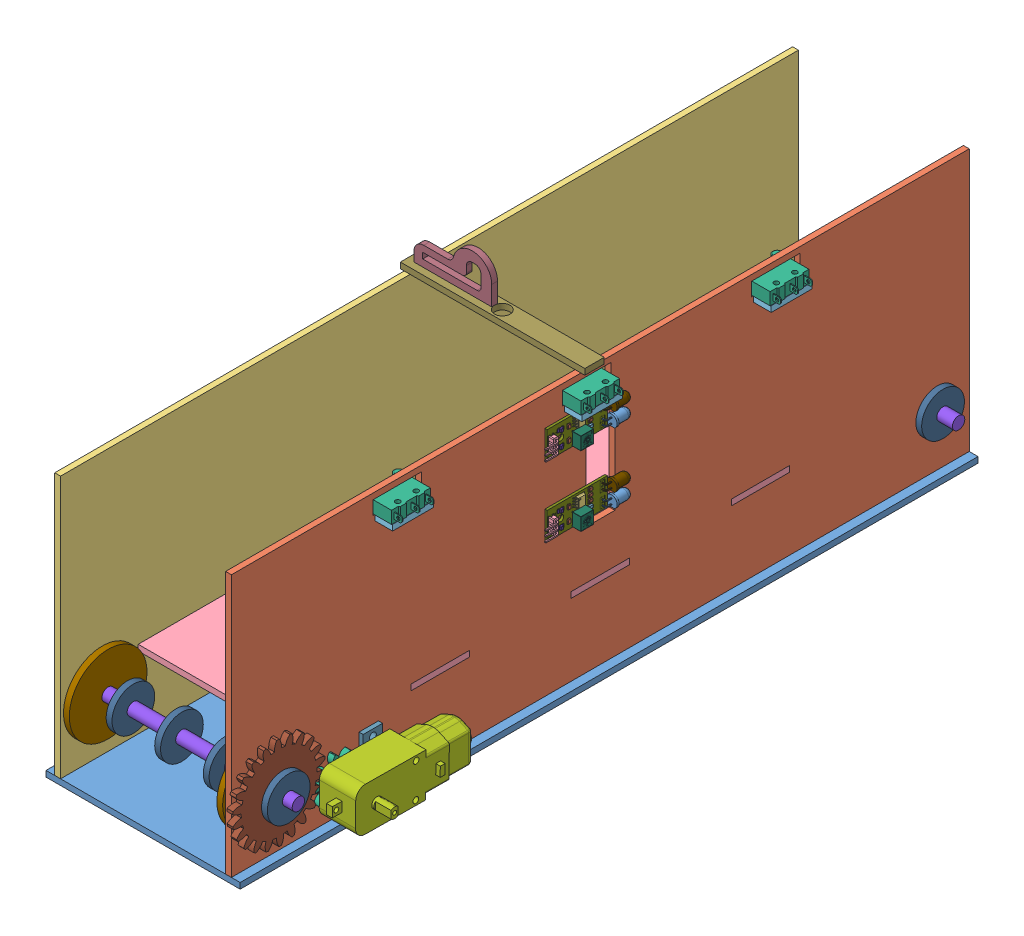
SolidWorks assembly EnsambleBandaConSensores, configuration Predeterminado. Lengths in mm.
Overall size (128.87 161.82 399.89).
68 component instances, 24 part files, 79 mates.
Components (placement in the parent):
- BAseGeneral-1: BAseGeneral [Predeterminado] at (-4.2266 -31.7563 350) size (100 3 380)
- ParedDerecha-2: ParedDerecha [Predeterminado] at (38.2734 38.7437 350) x (0 0 -1) z (1 0 0) size (380 138 3)
- ParedIzquierda-1: ParedIzquierda [Predeterminado] at (-46.7266 38.7437 350) x (0 0 1) z (-1 0 0) size (380 138 3)
- base-1: base [Predeterminado] at (-4.2266 8.2437 350) size (91 3 300)
- soporteFinCarrera-1: soporteFinCarrera [Predeterminado] at (38.2734 93.2437 265.5) x (0 0 -1) z (1 0 0) size (21 3 12)
- soporteFinCarrera-2: soporteFinCarrera [Predeterminado] at (38.2734 93.2437 460.5) x (0 0 -1) z (1 0 0) size (21 3 12)
- soporteFinCarrera-3: soporteFinCarrera [Predeterminado] at (38.2734 93.2437 363) x (0 0 -1) z (1 0 0) size (21 3 12)
- MiEngranePequeñoV2-1: MiEngranePequeñoV2 [Predeterminado] at (42.7734 384.4008 222.5284) x (0 -0.999961 0.008878) z (0 0.008878 0.999961) size (23.7 3 23.48)
- Motor-1: Motor [Predeterminado] at (65.5434 -8.5781 489.3215) x (0 -0.008878 -0.999961) z (0 0.999961 -0.008878) size (70.2 36.87 22.3)
- ejeRuedas-1: ejeRuedas [Predeterminado] at (55.7734 1.2437 520) x (0 1 0) z (0 0 1) size (6.4 110 6.4)
- RuedaGrande-1: RuedaGrande [Predeterminado] at (-42.2266 1.2437 520) x (0 1 0) z (0 0 1) size (40 3 40)
- RuedaGrande-2: RuedaGrande [Predeterminado] at (36.7734 1.2437 520) x (0 1 0) z (0 0 1) size (40 3 40)
- ruedaPequeña-1: ruedaPequeña [Predeterminado] at (-29.2266 1.2437 520) x (0 1 0) z (0 0 1) size (22 3 22)
- ruedaPequeña-2: ruedaPequeña [Predeterminado] at (-4.2266 1.2437 520) x (0 1 0) z (0 0 1) size (22 3 22)
- ruedaPequeña-3: ruedaPequeña [Predeterminado] at (20.7734 1.2437 520) x (0 1 0) z (0 0 1) size (22 3 22)
- EngraneGrande-1: EngraneGrande [Predeterminado] at (42.7734 -30.0906 1041.862) x (0 0.673646 -0.739054) z (1 0 0) size (48.01 47.68 3)
- ruedaPequeña-4: ruedaPequeña [Predeterminado] at (47.7734 1.2437 520) x (0 -1 0) z (0 0 1) size (22 3 22)
- ruedaPequeña-5: ruedaPequeña [Predeterminado] at (-53.2266 1.2437 520) x (0 -1 0) z (0 0 1) size (22 3 22)
- ejeRuedas-2: ejeRuedas [Predeterminado] at (55.7734 1.2437 180) x (0 1 0) z (0 0 1) size (6.4 110 6.4)
- ruedaPequeña-6: ruedaPequeña [Predeterminado] at (-50.2266 1.2437 180) x (0 1 0) z (0 0 1) size (22 3 22)
- ruedaPequeña-7: ruedaPequeña [Predeterminado] at (-4.2266 1.2437 180) x (0 1 0) z (0 0 1) size (22 3 22)
- ruedaPequeña-8: ruedaPequeña [Predeterminado] at (20.7734 1.2437 180) x (0 1 0) z (0 0 1) size (22 3 22)
- RuedaGrande-3: RuedaGrande [Predeterminado] at (-41.2266 1.2437 180) x (0 1 0) z (0 0 1) size (40 3 40)
- RuedaGrande-4: RuedaGrande [Predeterminado] at (32.7734 1.2437 180) x (0 -0.381849 0.924225) z (0 0.924225 0.381849) size (40 3 40)
- ruedaPequeña-9: ruedaPequeña [Predeterminado] at (47.7734 1.2437 180) x (0 1 0) z (0 0 1) size (22 3 22)
- ruedaPequeña-10: ruedaPequeña [Predeterminado] at (-29.2266 1.2437 180) x (0 1 0) z (0 0 1) size (22 3 22)
- Travesaño-1: Travesaño [Predeterminado] at (-4.2266 106.2437 355) size (95 3 10)
- GuiaMangera-1: GuiaMangera [Predeterminado] at (-28.1798 119.2437 353.5) size (40 23 3)
- SoporteMotor-1: SoporteMotor [Predeterminado] at (40.445 -8.7563 469.3) x (0 0 -1) z (1 0 0) size (10 24 3)
- Sensor_IR.stp-1: Sensor_IR.stp [Predeterminado] at (41.6734 48.2437 363.5) x (0 0 -1) z (1 0 0) size (45.22 14 7.87)
  - 3362P-1-102LF.stp-1: 3362P-1-102LF.stp [Predeterminado] at (0.5 -3.2 1.53) x (1 0 0) z (0 -1 0) size (6.6 7.58 6.6)
  - IR_Sensor_FC-51_1.stp-1: IR_Sensor_FC-51_1.stp [Predeterminado] at origin size (31 14 1.25)
  - KPTR-3216CGCK.stp-1: KPTR-3216CGCK.stp [Predeterminado] at (-8.7 3.8 1.45) x (1 0 0) z (0 0 -1) size (3.2 1.6 1.05)
  - KPTR-3216CGCK.stp-2: KPTR-3216CGCK.stp [Predeterminado] at (-8.7 -3.8 1.45) x (1 0 0) z (0 0 -1) size (3.2 1.6 1.05)
  - LED 5mm.stp-1: LED 5mm.stp [Predeterminado] at (15.74 3.64 3) x (0 1 0) z (1 0 0) size (5.5 6.7 11.78)
  - LED 5mm_foto.stp-1: LED 5mm_foto.stp [Predeterminado] at (15.74 -3.64 3) x (0 1 0) z (1 0 0) size (5.5 6.7 11.78)
  - RESC-0805.stp-1: RESC-0805.stp [Predeterminado] at (-4.525 -3.15 1.2) x (0 -1 0) z (0 0 1) size (2.1 1.35 0.6)
  - RESC-0805.stp-2: RESC-0805.stp [Predeterminado] at (-4.525 3.25 1.2) x (0 1 0) z (0 0 1) size (2.1 1.35 0.6)
  - SOIC8-150-50.stp-1: SOIC8-150-50.stp [Predeterminado] at (0.55 3.85 1.2) x (1 0 0) z (0 -1 0) size (6 1.91 4.9)
  - 1 Pin 2.54 mm Right Angle Single Row Pin Header Male 90 degrees Needle Connector.stp-1: 1 Pin 2.54 mm Right Angle Single Row Pin Header Male 90 degrees Needle Connector.stp [Predeterminado] at (-13.5 2.54 -1.76) x (-1 0 0) z (0 0 1) size (8.45 2.54 7.3)
  - 1 Pin 2.54 mm Right Angle Single Row Pin Header Male 90 degrees Needle Connector.stp-2: 1 Pin 2.54 mm Right Angle Single Row Pin Header Male 90 degrees Needle Connector.stp [Predeterminado] at (-13.5 0 -1.76) x (-1 0 0) z (0 0 1) size (8.45 2.54 7.3)
  - 1 Pin 2.54 mm Right Angle Single Row Pin Header Male 90 degrees Needle Connector.stp-3: 1 Pin 2.54 mm Right Angle Single Row Pin Header Male 90 degrees Needle Connector.stp [Predeterminado] at (-13.5 -2.54 -1.76) x (-1 0 0) z (0 0 1) size (8.45 2.54 7.3)
  - RESC-0805.stp-3: RESC-0805.stp [Predeterminado] at (6.45 5.625 1.2) size (2.1 1.35 0.6)
  - RESC-0805.stp-4: RESC-0805.stp [Predeterminado] at (6.45 3.085 1.2) size (2.1 1.35 0.6)
  - RESC-0805.stp-5: RESC-0805.stp [Predeterminado] at (6.45 0.545 1.2) size (2.1 1.35 0.6)
  - CAPC-0805-T0.95-BN.stp-1: CAPC-0805-T0.95-BN.stp [Predeterminado] at (6.45 -1.995 1.2) size (2.1 1.35 0.95)
  - CAPC-0805-T0.95-BN.stp-2: CAPC-0805-T0.95-BN.stp [Predeterminado] at (6.45 -4.535 1.2) size (2.1 1.35 0.95)
- Sensor_IR.stp-2: Sensor_IR.stp [Predeterminado] at (41.6734 84.2437 363.5) x (0 0 -1) z (1 0 0) size (45.22 14 7.87)
  - 3362P-1-102LF.stp-1: 3362P-1-102LF.stp [Predeterminado] at (0.5 -3.2 1.53) x (1 0 0) z (0 -1 0) size (6.6 7.58 6.6)
  - IR_Sensor_FC-51_1.stp-1: IR_Sensor_FC-51_1.stp [Predeterminado] at origin size (31 14 1.25)
  - KPTR-3216CGCK.stp-1: KPTR-3216CGCK.stp [Predeterminado] at (-8.7 3.8 1.45) x (1 0 0) z (0 0 -1) size (3.2 1.6 1.05)
  - KPTR-3216CGCK.stp-2: KPTR-3216CGCK.stp [Predeterminado] at (-8.7 -3.8 1.45) x (1 0 0) z (0 0 -1) size (3.2 1.6 1.05)
  - LED 5mm.stp-1: LED 5mm.stp [Predeterminado] at (15.74 3.64 3) x (0 1 0) z (1 0 0) size (5.5 6.7 11.78)
  - LED 5mm_foto.stp-1: LED 5mm_foto.stp [Predeterminado] at (15.74 -3.64 3) x (0 1 0) z (1 0 0) size (5.5 6.7 11.78)
  - RESC-0805.stp-1: RESC-0805.stp [Predeterminado] at (-4.525 -3.15 1.2) x (0 -1 0) z (0 0 1) size (2.1 1.35 0.6)
  - RESC-0805.stp-2: RESC-0805.stp [Predeterminado] at (-4.525 3.25 1.2) x (0 1 0) z (0 0 1) size (2.1 1.35 0.6)
  - SOIC8-150-50.stp-1: SOIC8-150-50.stp [Predeterminado] at (0.55 3.85 1.2) x (1 0 0) z (0 -1 0) size (6 1.91 4.9)
  - 1 Pin 2.54 mm Right Angle Single Row Pin Header Male 90 degrees Needle Connector.stp-1: 1 Pin 2.54 mm Right Angle Single Row Pin Header Male 90 degrees Needle Connector.stp [Predeterminado] at (-13.5 2.54 -1.76) x (-1 0 0) z (0 0 1) size (8.45 2.54 7.3)
  - 1 Pin 2.54 mm Right Angle Single Row Pin Header Male 90 degrees Needle Connector.stp-2: 1 Pin 2.54 mm Right Angle Single Row Pin Header Male 90 degrees Needle Connector.stp [Predeterminado] at (-13.5 0 -1.76) x (-1 0 0) z (0 0 1) size (8.45 2.54 7.3)
  - 1 Pin 2.54 mm Right Angle Single Row Pin Header Male 90 degrees Needle Connector.stp-3: 1 Pin 2.54 mm Right Angle Single Row Pin Header Male 90 degrees Needle Connector.stp [Predeterminado] at (-13.5 -2.54 -1.76) x (-1 0 0) z (0 0 1) size (8.45 2.54 7.3)
  - RESC-0805.stp-3: RESC-0805.stp [Predeterminado] at (6.45 5.625 1.2) size (2.1 1.35 0.6)
  - RESC-0805.stp-4: RESC-0805.stp [Predeterminado] at (6.45 3.085 1.2) size (2.1 1.35 0.6)
  - RESC-0805.stp-5: RESC-0805.stp [Predeterminado] at (6.45 0.545 1.2) size (2.1 1.35 0.6)
  - CAPC-0805-T0.95-BN.stp-1: CAPC-0805-T0.95-BN.stp [Predeterminado] at (6.45 -1.995 1.2) size (2.1 1.35 0.95)
  - CAPC-0805-T0.95-BN.stp-2: CAPC-0805-T0.95-BN.stp [Predeterminado] at (6.45 -4.535 1.2) size (2.1 1.35 0.95)
- Fin_Carrera.step-1: Fin_Carrera.step [Predeterminado] at (44.9634 96.2437 456.35) x (0 0 1) z (0 -1 0) size (22.47 22.8 6.34)
- Fin_Carrera.step-2: Fin_Carrera.step [Predeterminado] at (44.9634 96.2437 358.85) x (0 0 1) z (0 -1 0) size (22.47 22.8 6.34)
- Fin_Carrera.step-3: Fin_Carrera.step [Predeterminado] at (44.9634 96.2437 261.35) x (0 0 1) z (0 -1 0) size (22.47 22.8 6.34)
Mates (geometry in assembly coordinates):
- Coincidente2: coincident anti-aligned: plane of BAseGeneral-1 through (41.2734 -28.7563 417.5) normal (-1 0 0); plane of ParedDerecha-2 through (41.2734 38.7437 350) normal (1 0 0)
- Coincidente4: coincident anti-aligned: plane of BAseGeneral-1 through (38.2734 -28.7563 447.5) normal (0 0 -1); plane of ParedDerecha-2 through (41.2734 38.7437 447.5) normal (0 0 1)
- Coincidente5: coincident aligned: plane of BAseGeneral-1 through (-4.2266 -31.7563 350) normal (0 -1 0); plane of ParedDerecha-2 through (41.2734 -31.7563 350) normal (0 -1 0)
- Coincidente6: coincident anti-aligned: plane of BAseGeneral-1 through (-49.7266 -28.7563 417.5) normal (1 0 0); plane of ParedIzquierda-1 through (-49.7266 38.7437 350) normal (-1 0 0)
- Coincidente7: coincident anti-aligned: plane of BAseGeneral-1 through (-49.7266 -28.7563 447.5) normal (0 0 -1); plane of ParedIzquierda-1 through (-49.7266 -31.7563 447.5) normal (0 0 1)
- Coincidente8: coincident aligned: plane of BAseGeneral-1 through (-4.2266 -31.7563 350) normal (0 -1 0); plane of ParedIzquierda-1 through (-49.7266 -31.7563 335) normal (0 -1 0)
- Coincidente9: coincident aligned: plane of ParedDerecha-2 through (41.2734 38.7437 350) normal (1 0 0); plane of base-1 through (41.2734 11.2437 447.5) normal (1 0 0)
- Coincidente10: coincident anti-aligned: plane of ParedDerecha-2 through (41.2734 38.7437 447.5) normal (0 0 -1); plane of base-1 through (38.2734 11.2437 447.5) normal (0 0 1)
- Coincidente11: coincident anti-aligned: plane of ParedDerecha-2 through (41.2734 11.2437 350) normal (0 -1 0); plane of base-1 through (-4.2266 11.2437 350) normal (0 1 0)
- Coincidente12: coincident anti-aligned: plane of ParedDerecha-2 through (41.2734 93.2437 350) normal (0 1 0); plane of soporteFinCarrera-2 through (38.2734 93.2437 460.5) normal (0 -1 0)
- Coincidente13: coincident anti-aligned: plane of ParedDerecha-2 through (41.2734 38.7437 450.5) normal (0 0 1); plane of soporteFinCarrera-2 through (38.2734 96.2437 450.5) normal (0 0 -1)
- Coincidente14: coincident aligned: plane of ParedDerecha-2 through (38.2734 38.7437 350) normal (-1 0 0); plane of soporteFinCarrera-2 through (38.2734 96.2437 460.5) normal (-1 0 0)
- Coincidente15: coincident anti-aligned: plane of ParedDerecha-2 through (41.2734 93.2437 350) normal (0 1 0); plane of soporteFinCarrera-3 through (38.2734 93.2437 363) normal (0 -1 0)
- Coincidente16: coincident anti-aligned: plane of ParedDerecha-2 through (41.2734 38.7437 353) normal (0 0 1); plane of soporteFinCarrera-3 through (38.2734 96.2437 353) normal (0 0 -1)
- Coincidente17: coincident aligned: plane of ParedDerecha-2 through (38.2734 38.7437 350) normal (-1 0 0); plane of soporteFinCarrera-3 through (38.2734 96.2437 363) normal (-1 0 0)
- Coincidente18: coincident anti-aligned: plane of ParedDerecha-2 through (41.2734 93.2437 350) normal (0 1 0); plane of soporteFinCarrera-1 through (38.2734 93.2437 265.5) normal (0 -1 0)
- Coincidente19: coincident anti-aligned: plane of ParedDerecha-2 through (41.2734 38.7437 255.5) normal (0 0 1); plane of soporteFinCarrera-1 through (38.2734 96.2437 255.5) normal (0 0 -1)
- Coincidente20: coincident aligned: plane of ParedDerecha-2 through (38.2734 38.7437 350) normal (-1 0 0); plane of soporteFinCarrera-1 through (38.2734 96.2437 265.5) normal (-1 0 0)
- Coincidente23: coincident anti-aligned: plane of MiEngranePequeñoV2-1 through (45.7734 386.7548 487.6616) normal (0 -0.008878 -0.999961); plane of Motor-1 through (45.7734 -8.5617 491.1715) normal (0 0.008878 0.999961)
- Coincidente24: coincident anti-aligned: plane of MiEngranePequeñoV2-1 through (45.7734 384.4008 222.5284) normal (1 0 0); plane of Motor-1 through (45.7734 -8.5781 489.3215) normal (-1 0 0)
- Coincidente26: coincident aligned: line of MiEngranePequeñoV2-1 through (45.7734 -10.4938 491.1886) axis (-1 0 0); line of Motor-1 through (45.7734 -10.4938 491.1886) axis (-1 0 0)
- Coincidente27: coincident anti-aligned: cylinder of ejeRuedas-1 through (-54.2266 1.2437 520) axis (1 0 0) radius 3.2; circle of RuedaGrande-1
- Concéntrica7: concentric aligned: cylinder of ejeRuedas-1 through (-54.2266 1.2437 520) axis (1 0 0) radius 3.2; cylinder of RuedaGrande-2 through (33.7734 1.2437 520) axis (1 0 0) radius 3.2
- Distancia2: distance = 9 mm aligned: plane of RuedaGrande-1 through (-45.2266 1.2437 520) normal (-1 0 0); plane of ejeRuedas-1 through (-54.2266 1.2437 520) normal (-1 0 0)
- Distancia3: distance = 19 mm aligned: plane of RuedaGrande-2 through (36.7734 1.2437 520) normal (1 0 0); plane of ejeRuedas-1 through (55.7734 1.2437 520) normal (1 0 0)
- Concéntrica8: concentric aligned: cylinder of ejeRuedas-1 through (-54.2266 1.2437 520) axis (1 0 0) radius 3.2; cylinder of ruedaPequeña-1 through (-32.2266 1.2437 520) axis (1 0 0) radius 3.2
- Distancia4: distance = 85 mm aligned: plane of ruedaPequeña-1 through (-29.2266 1.2437 520) normal (1 0 0); plane of ejeRuedas-1 through (55.7734 1.2437 520) normal (1 0 0)
- Concéntrica9: concentric aligned: cylinder of ejeRuedas-1 through (-54.2266 1.2437 520) axis (1 0 0) radius 3.2; cylinder of ruedaPequeña-2 through (-7.2266 1.2437 520) axis (1 0 0) radius 3.2
- Distancia5: distance = 60 mm aligned: plane of ruedaPequeña-2 through (-4.2266 1.2437 520) normal (1 0 0); plane of ejeRuedas-1 through (55.7734 1.2437 520) normal (1 0 0)
- Concéntrica10: concentric aligned: cylinder of ejeRuedas-1 through (-54.2266 1.2437 520) axis (1 0 0) radius 3.2; cylinder of ruedaPequeña-3 through (17.7734 1.2437 520) axis (1 0 0) radius 3.2
- Distancia6: distance = 35 mm aligned: plane of ruedaPequeña-3 through (20.7734 1.2437 520) normal (1 0 0); plane of ejeRuedas-1 through (55.7734 1.2437 520) normal (1 0 0)
- Concéntrica11: concentric anti-aligned: cylinder of ParedDerecha-2 through (41.2734 1.2437 520) axis (-1 0 0) radius 3.5; cylinder of ejeRuedas-1 through (-54.2266 1.2437 520) axis (1 0 0) radius 3.2
- Tangente3: tangent anti-aligned: cylinder of ejeRuedas-1 through (-54.2266 1.2437 520) axis (1 0 0) radius 3.2; face of EngraneGrande-1
- Distancia7: distance = 10 mm aligned: plane of ejeRuedas-1 through (55.7734 1.2437 520) normal (1 0 0); plane of EngraneGrande-1 through (45.7734 -20.0408 514.8334) normal (1 0 0)
- Coincidente38: coincident aligned: plane of MiEngranePequeñoV2-1 through (45.7734 384.4008 222.5284) normal (1 0 0); plane of EngraneGrande-1 through (45.7734 -20.0408 514.8334) normal (1 0 0)
- Concéntrica12: concentric aligned: cylinder of ParedDerecha-2 through (41.2734 -17.5063 469.3) axis (-1 0 0) radius 2; cylinder of Motor-1 through (74.6434 -17.5063 469.3) axis (-1 0 0) radius 1.5
- Paralelo3: parallel aligned: cylinder of ParedDerecha-2 through (41.2734 -0.0063 469.3) axis (-1 0 0) radius 2; cylinder of Motor-1 through (74.6434 -0.0069 469.1446) axis (-1 0 0) radius 1.5
- Coincidente39: coincident aligned: plane of BAseGeneral-1 through (-54.2266 -28.7563 540) normal (-1 0 0); plane of ejeRuedas-1 through (-54.2266 1.2437 520) normal (-1 0 0)
- Concéntrica14: concentric anti-aligned: cylinder of ejeRuedas-1 through (-54.2266 1.2437 520) axis (1 0 0) radius 3.2; cylinder of ruedaPequeña-4 through (50.7734 1.2437 520) axis (-1 0 0) radius 3.2
- Distancia8: distance = 5 mm aligned: plane of ruedaPequeña-4 through (50.7734 1.2437 520) normal (1 0 0); plane of ejeRuedas-1 through (55.7734 1.2437 520) normal (1 0 0)
- Concéntrica16: concentric anti-aligned: cylinder of ejeRuedas-1 through (-54.2266 1.2437 520) axis (1 0 0) radius 3.2; cylinder of ruedaPequeña-5 through (-50.2266 1.2437 520) axis (-1 0 0) radius 3.2
- Distancia9: distance = 1 mm aligned: plane of ruedaPequeña-5 through (-53.2266 1.2437 520) normal (-1 0 0); plane of ejeRuedas-1 through (-54.2266 1.2437 520) normal (-1 0 0)
- Concéntrica17: concentric aligned: cylinder of ejeRuedas-2 through (-54.2266 1.2437 180) axis (1 0 0) radius 3.2; cylinder of ruedaPequeña-10 through (-32.2266 1.2437 180) axis (1 0 0) radius 3.2
- Concéntrica18: concentric anti-aligned: cylinder of ejeRuedas-2 through (-54.2266 1.2437 180) axis (1 0 0) radius 3.2; cylinder of RuedaGrande-4 through (35.7734 1.2437 180) axis (-1 0 0) radius 3.2
- Coincidente42: coincident anti-aligned: cylinder of ejeRuedas-2 through (-54.2266 1.2437 180) axis (1 0 0) radius 3.2; circle of ruedaPequeña-8
- Concéntrica19: concentric aligned: cylinder of ejeRuedas-2 through (-54.2266 1.2437 180) axis (1 0 0) radius 3.2; cylinder of ruedaPequeña-7 through (-7.2266 1.2437 180) axis (1 0 0) radius 3.2
- Concéntrica20: concentric aligned: cylinder of ejeRuedas-2 through (-54.2266 1.2437 180) axis (1 0 0) radius 3.2; cylinder of ruedaPequeña-6 through (-53.2266 1.2437 180) axis (1 0 0) radius 3.2
- Concéntrica21: concentric aligned: cylinder of ejeRuedas-2 through (-54.2266 1.2437 180) axis (1 0 0) radius 3.2; cylinder of RuedaGrande-3 through (-44.2266 1.2437 180) axis (1 0 0) radius 3.2
- Concéntrica22: concentric aligned: cylinder of ejeRuedas-2 through (-54.2266 1.2437 180) axis (1 0 0) radius 3.2; cylinder of ruedaPequeña-9 through (44.7734 1.2437 180) axis (1 0 0) radius 3.2
- Concéntrica23: concentric anti-aligned: circle of ParedIzquierda-1; cylinder of ejeRuedas-2 through (-54.2266 1.2437 180) axis (1 0 0) radius 3.2
- Coincidente43: coincident aligned: plane of BAseGeneral-1 through (-54.2266 -28.7563 540) normal (-1 0 0); plane of ejeRuedas-2 through (-54.2266 1.2437 180) normal (-1 0 0)
- Distancia10: distance = 97 mm aligned: plane of RuedaGrande-3 through (-41.2266 1.2437 180) normal (1 0 0); plane of ejeRuedas-2 through (55.7734 1.2437 180) normal (1 0 0)
- Distancia11: distance = 23 mm anti-aligned: plane of ejeRuedas-2 through (55.7734 1.2437 180) normal (1 0 0); plane of RuedaGrande-4 through (32.7734 1.2437 180) normal (-1 0 0)
- Distancia12: distance = 106 mm aligned: plane of ruedaPequeña-6 through (-50.2266 1.2437 180) normal (1 0 0); plane of ejeRuedas-2 through (55.7734 1.2437 180) normal (1 0 0)
- Distancia13: distance = 35 mm aligned: plane of ruedaPequeña-8 through (20.7734 1.2437 180) normal (1 0 0); plane of ejeRuedas-2 through (55.7734 1.2437 180) normal (1 0 0)
- Distancia14: distance = 60 mm aligned: plane of ruedaPequeña-7 through (-4.2266 1.2437 180) normal (1 0 0); plane of ejeRuedas-2 through (55.7734 1.2437 180) normal (1 0 0)
- Distancia15: distance = 85 mm aligned: plane of ruedaPequeña-10 through (-29.2266 1.2437 180) normal (1 0 0); plane of ejeRuedas-2 through (55.7734 1.2437 180) normal (1 0 0)
- Distancia16: distance = 8 mm aligned: plane of ruedaPequeña-9 through (47.7734 1.2437 180) normal (1 0 0); plane of ejeRuedas-2 through (55.7734 1.2437 180) normal (1 0 0)
- Coincidente51: coincident anti-aligned: plane of ParedDerecha-2 through (41.2734 106.2437 350) normal (0 1 0); plane of Travesaño-1 through (-4.2266 106.2437 355) normal (0 -1 0)
- Distancia17: distance = 2 mm aligned: plane of Travesaño-1 through (43.2734 109.2437 360) normal (1 0 0); plane of ParedDerecha-2 through (41.2734 38.7437 350) normal (1 0 0)
- Distancia18: distance = 190 mm aligned: plane of Travesaño-1 through (-51.7266 109.2437 350) normal (0 0 -1); plane of ParedDerecha-2 through (41.2734 38.7437 160) normal (0 0 -1)
- Coincidente54: coincident anti-aligned: plane of Travesaño-1 through (-43.7266 109.2437 356.5) normal (0 0 -1); plane of GuiaMangera-1 through (-18.1798 119.2437 356.5) normal (0 0 1)
- Coincidente55: coincident anti-aligned: plane of Travesaño-1 through (-43.7266 109.2437 356.5) normal (1 0 0); plane of GuiaMangera-1 through (-43.7266 109.2437 356.5) normal (-1 0 0)
- Coincidente56: coincident aligned: plane of Travesaño-1 through (-4.2266 106.2437 355) normal (0 -1 0); plane of GuiaMangera-1 through (-43.7266 106.2437 356.5) normal (0 -1 0)
- Concéntrica24: concentric anti-aligned: cylinder of ParedDerecha-2 through (41.2734 -0.0063 469.3) axis (-1 0 0) radius 2; circle of SoporteMotor-1
- Concéntrica25: concentric aligned: cylinder of ParedDerecha-2 through (41.2734 -17.5063 469.3) axis (-1 0 0) radius 2; cylinder of SoporteMotor-1 through (43.445 -17.5063 469.3) axis (-1 0 0) radius 1.75
- Distancia19: distance = 0.4 mm: plane of Sensor_IR.stp-2/IR_Sensor_FC-51_1.stp-1 through (41.6734 84.2437 363.5) normal (-1 0 0); plane of ParedDerecha-2 through (41.2734 38.7437 350) normal (1 0 0)
- Coincidente59: coincident aligned: cylinder of ParedDerecha-2 through (41.2734 84.2437 372) axis (-1 0 0) radius 1.5; circle of Sensor_IR.stp-2/IR_Sensor_FC-51_1.stp-1
- Distancia20: distance = 0.4 mm: plane of Sensor_IR.stp-1/IR_Sensor_FC-51_1.stp-1 through (41.6734 48.2437 363.5) normal (-1 0 0); plane of ParedDerecha-2 through (41.2734 38.7437 350) normal (1 0 0)
- Concéntrica26: concentric anti-aligned: cylinder of ParedDerecha-2 through (41.2734 48.2437 372) axis (-1 0 0) radius 1.5; cylinder of Sensor_IR.stp-1/IR_Sensor_FC-51_1.stp-1 through (41.6734 48.2437 372) axis (1 0 0) radius 1.5
- Coincidente61: coincident: plane of soporteFinCarrera-2 through (38.2734 96.2437 460.5) normal (0 1 0); plane of Fin_Carrera.step-1 through (45.2684 96.2437 456.35) normal (0 -1 0)
- Concéntrica27: concentric: cylinder of soporteFinCarrera-2 through (47.7734 96.2437 460.85) axis (0 -1 0) radius 1.175; cylinder of Fin_Carrera.step-1 through (47.7734 96.2437 460.85) axis (0 1 0) radius 1.25
- Concéntrica28: concentric anti-aligned: cylinder of soporteFinCarrera-2 through (47.7734 96.2437 451.35) axis (0 -1 0) radius 1.175; cylinder of Fin_Carrera.step-1 through (47.7734 96.2437 451.35) axis (0 1 0) radius 1.25
- Coincidente62: coincident: plane of soporteFinCarrera-3 through (38.2734 96.2437 363) normal (0 1 0); plane of Fin_Carrera.step-2 through (45.2684 96.2437 358.85) normal (0 -1 0)
- Concéntrica29: concentric: cylinder of soporteFinCarrera-3 through (47.7734 96.2437 363.35) axis (0 -1 0) radius 1.175; cylinder of Fin_Carrera.step-2 through (47.7734 96.2437 363.35) axis (0 1 0) radius 1.25
- Concéntrica30: concentric aligned: circle of soporteFinCarrera-3; cylinder of Fin_Carrera.step-2 through (47.7734 96.2437 353.85) axis (0 1 0) radius 1.25
- Coincidente63: coincident: plane of soporteFinCarrera-1 through (38.2734 96.2437 265.5) normal (0 1 0); plane of Fin_Carrera.step-3 through (45.2684 96.2437 261.35) normal (0 -1 0)
- Concéntrica31: concentric: cylinder of soporteFinCarrera-1 through (47.7734 96.2437 265.85) axis (0 -1 0) radius 1.175; cylinder of Fin_Carrera.step-3 through (47.7734 96.2437 265.85) axis (0 1 0) radius 1.25
- Concéntrica32: concentric anti-aligned: axis of soporteFinCarrera-1 through (47.7734 96.2437 256.35) axis (0 -1 0); cylinder of Fin_Carrera.step-3 through (47.7734 96.2437 256.35) axis (0 1 0) radius 1.25
